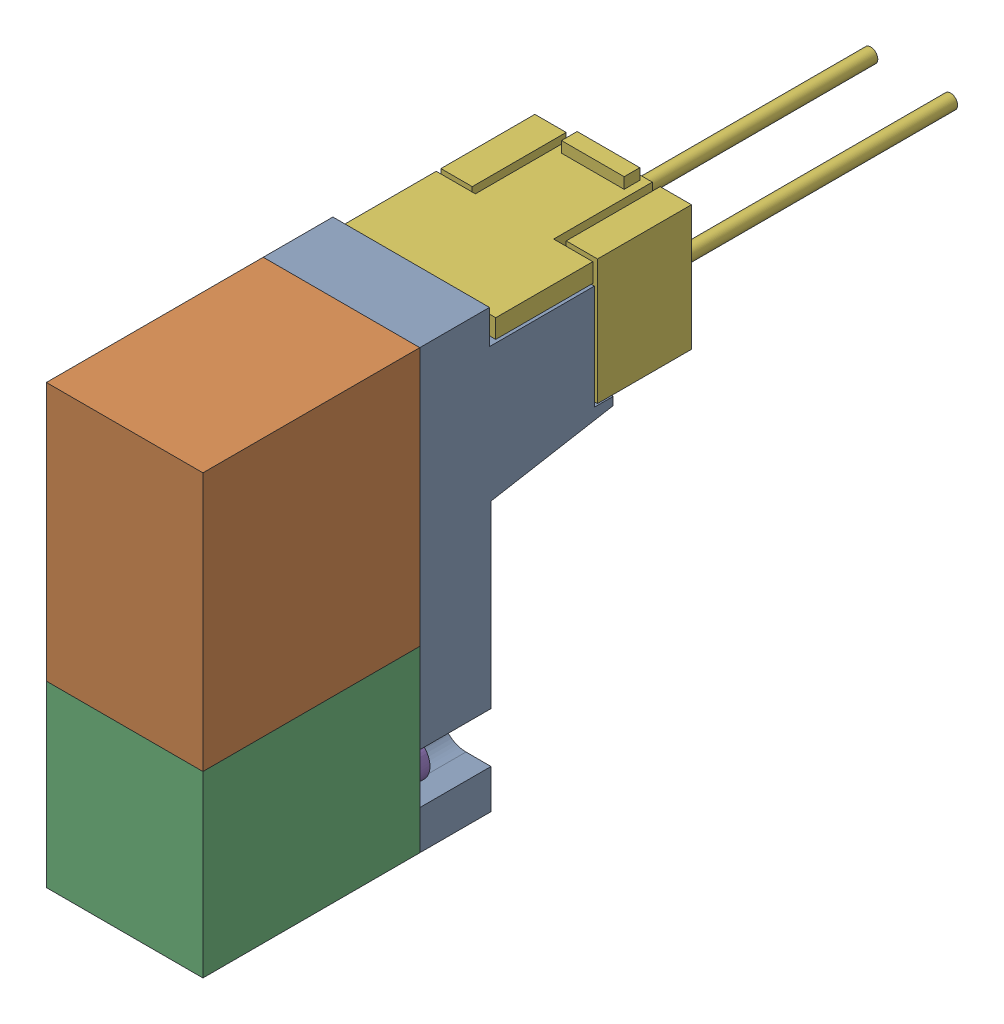
SolidWorks assembly 4GA129-M5-E01-4_D_100000_4G-Coil-SubASSY_01(EDC-E-H)-1, configuration Default. Lengths in mm.
Overall size (10 27.94 50.2).
2 component instances, 2 part files, 0 mates.
Components (placement in the parent):
- 4GA129-M5-E01-4_D_000102_4GcoilEDC_00(Default)-1: 4GA129-M5-E01-4_D_000102_4GcoilEDC_00(Default) [Default] at origin size (10 27.94 26.2)
- 4GA129-M5-E01-4_D_000123_4GSocketAssyE_00(Default)-1: 4GA129-M5-E01-4_D_000123_4GSocketAssyE_00(Default) [Default] at (0 22.17 -25.2) size (10 8.7 31.5)
